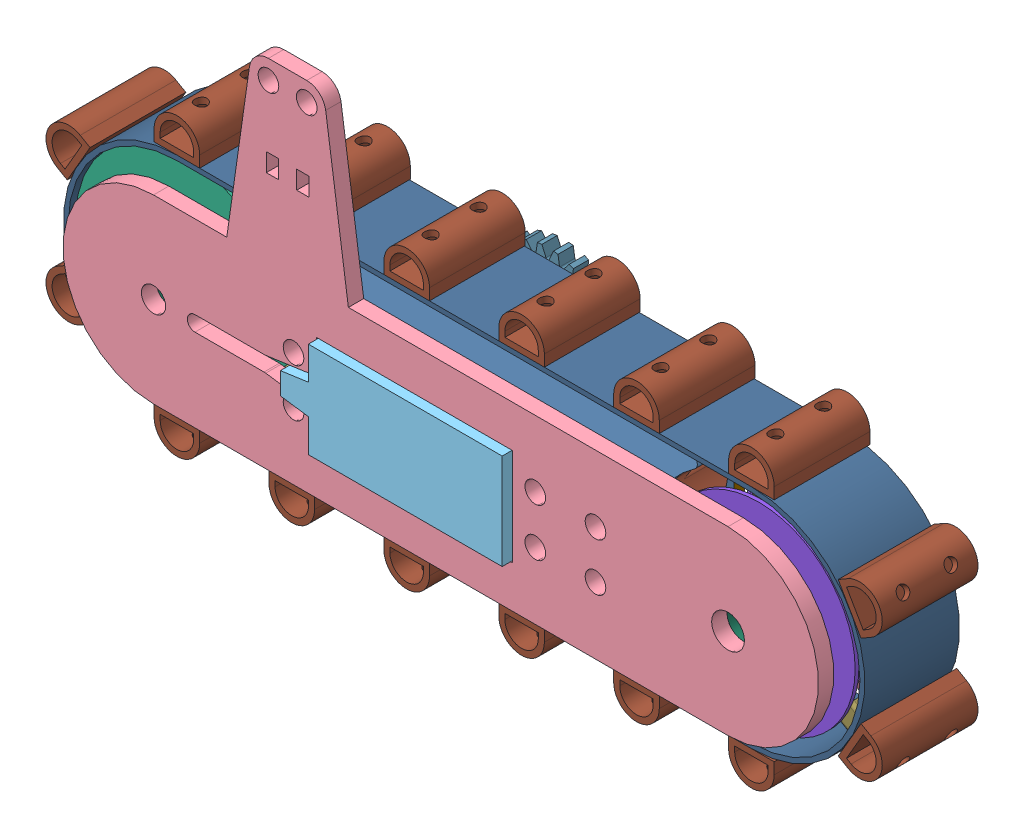
SolidWorks assembly DriveTread Assembly_L, configuration Default. Lengths in mm.
Overall size (178.72 86.46 42.8).
83 component instances, 16 part files, 32 mates.
Components (placement in the parent):
- tread runner-3: tread runner [Default] at (113.4402 41.5963 5.7004) x (-1 0 0) z (0 0 1) size (94.4 45.38 1.65)
- drive spacer_mid-1: drive spacer_mid [Default] at (14.0238 -0.101 14.8444) size (83.18 38.02 14.99)
- tread runner-4: tread runner [Default] at (113.4402 41.5963 22.3374) x (-1 0 0) z (0 0 1) size (94.4 45.38 1.65)
- drive spacer_out-1: drive spacer_out [Default] at (19.9176 6.2078 23.9884) size (78.33 25.4 3.2)
- drive plate_out-1: drive plate_out [Default] at (0 0 27.1888) size (157.83 74.53 3.2)
- Servo_ContRotation-3: Servo_ContRotation [Default] at (74.747 28.9078 5.7004) x (0 -1 0) z (0 0 -1) size (20 55.5 42.8)
- DriveWheel-4: DriveWheel [Default] at (15.6211 -3.6734 -29.9998) x (0.924613 0.380909 0) z (0 0 1) size (45.38 45.43 18.29)
  - Custom Axle Drive_LEGO UWheel_6x3-1: Custom Axle Drive_LEGO UWheel_6x3 [Default] at (-5.8421 26.8291 44.8442) size (45.38 45.43 18.29)
  - WheelPlates w-Custom Axle-1: WheelPlates w-Custom Axle [Default] at (-5.8421 26.8291 50.737) x (0.5 -0.866025 0) z (0 0 1) size (28.95 30.08 3.2)
  - WheelPlates w-Custom Axle-2: WheelPlates w-Custom Axle [Default] at (-5.8421 26.8291 35.751) x (0.5 -0.866025 0) z (0 0 1) size (28.95 30.08 3.2)
- Custom Axle Float_LEGO UWheel_6xRR2-5: Custom Axle Float_LEGO UWheel_6xRR2 [Default] at (120.015 18.9078 14.8444) x (0.969727 -0.244192 0) z (0 0 1) size (40.3 40.3 18.29)
- drive spacer_in-4: drive spacer_in [Default] at (88.0272 6.2078 3.389) x (1 0 0) z (0 0 1) size (12.43 25.4 2.31)
- tread-2: tread [Default] at (0 -3.7808 15.6064) size (178.18 61.66 20)
  - tread_base-1: tread_base [Default] at origin size (167.39 47.38 19.81)
  - D-Lug_Terrain-1: D-Lug_Terrain [Default] at (0 48.7584 -10.094) size (9.53 7.14 20)
  - D-Lug_Terrain-2: D-Lug_Terrain [Default] at (-22.5771 35.7234 -10.094) x (0.5 0.866025 0) z (0 0 1) size (9.53 7.14 20)
  - D-Lug_Terrain-3: D-Lug_Terrain [Default] at (-22.5771 9.6536 -10.094) x (-0.5 0.866025 0) z (0 0 1) size (9.53 7.14 20)
  - D-Lug_Terrain-4: D-Lug_Terrain [Default] at (0 -3.3813 -10.094) x (-1 0 0) z (0 0 1) size (9.53 7.14 20)
  - D-Lug_Terrain-6: D-Lug_Terrain [Default] at (24.003 48.7584 -10.094) size (9.53 7.14 20)
  - D-Lug_Terrain-7: D-Lug_Terrain [Default] at (48.006 48.7584 -10.094) size (9.53 7.14 20)
  - D-Lug_Terrain-8: D-Lug_Terrain [Default] at (72.009 48.7584 -10.094) size (9.53 7.14 20)
  - D-Lug_Terrain-9: D-Lug_Terrain [Default] at (96.012 48.7584 -10.094) size (9.53 7.14 20)
  - D-Lug_Terrain-10: D-Lug_Terrain [Default] at (120.015 48.7584 -10.094) size (9.53 7.14 20)
  - D-Lug_Terrain-11: D-Lug_Terrain [Default] at (24.003 -3.3813 -10.094) x (-1 0 0) z (0 0 1) size (9.53 7.14 20)
  - D-Lug_Terrain-12: D-Lug_Terrain [Default] at (48.006 -3.3813 -10.094) x (-1 0 0) z (0 0 1) size (9.53 7.14 20)
  - D-Lug_Terrain-13: D-Lug_Terrain [Default] at (72.009 -3.3813 -10.094) x (-1 0 0) z (0 0 1) size (9.53 7.14 20)
  - D-Lug_Terrain-14: D-Lug_Terrain [Default] at (96.012 -3.3813 -10.094) x (-1 0 0) z (0 0 1) size (9.53 7.14 20)
  - D-Lug_Terrain-15: D-Lug_Terrain [Default] at (142.5921 35.7234 -10.094) x (0.5 -0.866025 0) z (0 0 1) size (9.53 7.14 20)
  - D-Lug_Terrain-16: D-Lug_Terrain [Default] at (142.5921 9.6536 -10.094) x (-0.5 -0.866025 0) z (0 0 1) size (9.53 7.14 20)
  - D-Lug_Terrain-17: D-Lug_Terrain [Default] at (120.015 -3.3813 -10.094) x (-1 0 0) z (0 0 1) size (9.53 7.14 20)
  - DriveLug_x-1: DriveLug_x [Default] at (-2.7045 0 0) size (5.84 6.24 14.92)
    - Drive Lug_x-1: Drive Lug_x [Default] at origin size (5.41 3.2 14.92)
    - 97334A104_NYLON SOCKET HEAD CAP SCREW-1: 97334A104_NYLON SOCKET HEAD CAP SCREW [97334A104] at (2.7045 0.0254 0) x (0.302379 0 0.953188) z (0 -1 0) size (4.65 4.65 6.24)
  - DriveLug_x-2: DriveLug_x [Default] at (-21.0011 13.6864 0) x (0.5 -0.866025 0) z (0 0 1) size (5.84 6.24 14.92)
    - Drive Lug_x-1: Drive Lug_x [Default] at origin size (5.41 3.2 14.92)
    - 97334A104_NYLON SOCKET HEAD CAP SCREW-1: 97334A104_NYLON SOCKET HEAD CAP SCREW [97334A104] at (2.7045 0.0254 0) x (0.302379 0 0.953188) z (0 -1 0) size (4.65 4.65 6.24)
  - DriveLug_x-3: DriveLug_x [Default] at (-18.2966 36.375 0) x (-0.5 -0.866025 0) z (0 0 1) size (5.84 6.24 14.92)
    - Drive Lug_x-1: Drive Lug_x [Default] at origin size (5.41 3.2 14.92)
    - 97334A104_NYLON SOCKET HEAD CAP SCREW-1: 97334A104_NYLON SOCKET HEAD CAP SCREW [97334A104] at (2.7045 0.0254 0) x (0.302379 0 0.953188) z (0 -1 0) size (4.65 4.65 6.24)
  - DriveLug_x-4: DriveLug_x [Default] at (2.7045 45.3771 0) x (-1 0 0) z (0 0 1) size (5.84 6.24 14.92)
    - Drive Lug_x-1: Drive Lug_x [Default] at origin size (5.41 3.2 14.92)
    - 97334A104_NYLON SOCKET HEAD CAP SCREW-1: 97334A104_NYLON SOCKET HEAD CAP SCREW [97334A104] at (2.7045 0.0254 0) x (0.302379 0 0.953188) z (0 -1 0) size (4.65 4.65 6.24)
  - DriveLug_x-5: DriveLug_x [Default] at (21.2985 0 0) size (5.84 6.24 14.92)
    - Drive Lug_x-1: Drive Lug_x [Default] at origin size (5.41 3.2 14.92)
    - 97334A104_NYLON SOCKET HEAD CAP SCREW-1: 97334A104_NYLON SOCKET HEAD CAP SCREW [97334A104] at (2.7045 0.0254 0) x (0.302379 0 0.953188) z (0 -1 0) size (4.65 4.65 6.24)
  - DriveLug_x-6: DriveLug_x [Default] at (45.3015 0 0) size (5.84 6.24 14.92)
    - Drive Lug_x-1: Drive Lug_x [Default] at origin size (5.41 3.2 14.92)
    - 97334A104_NYLON SOCKET HEAD CAP SCREW-1: 97334A104_NYLON SOCKET HEAD CAP SCREW [97334A104] at (2.7045 0.0254 0) x (0.302379 0 0.953188) z (0 -1 0) size (4.65 4.65 6.24)
  - DriveLug_x-7: DriveLug_x [Default] at (69.3045 0 0) size (5.84 6.24 14.92)
    - Drive Lug_x-1: Drive Lug_x [Default] at origin size (5.41 3.2 14.92)
    - 97334A104_NYLON SOCKET HEAD CAP SCREW-1: 97334A104_NYLON SOCKET HEAD CAP SCREW [97334A104] at (2.7045 0.0254 0) x (0.302379 0 0.953188) z (0 -1 0) size (4.65 4.65 6.24)
  - DriveLug_x-8: DriveLug_x [Default] at (93.3075 0 0) size (5.84 6.24 14.92)
    - Drive Lug_x-1: Drive Lug_x [Default] at origin size (5.41 3.2 14.92)
    - 97334A104_NYLON SOCKET HEAD CAP SCREW-1: 97334A104_NYLON SOCKET HEAD CAP SCREW [97334A104] at (2.7045 0.0254 0) x (0.302379 0 0.953188) z (0 -1 0) size (4.65 4.65 6.24)
  - DriveLug_x-9: DriveLug_x [Default] at (117.3105 0 0) size (5.84 6.24 14.92)
    - Drive Lug_x-1: Drive Lug_x [Default] at origin size (5.41 3.2 14.92)
    - 97334A104_NYLON SOCKET HEAD CAP SCREW-1: 97334A104_NYLON SOCKET HEAD CAP SCREW [97334A104] at (2.7045 0.0254 0) x (0.302379 0 0.953188) z (0 -1 0) size (4.65 4.65 6.24)
  - DriveLug_x-10: DriveLug_x [Default] at (138.3116 9.0021 0) x (0.5 0.866025 0) z (0 0 1) size (5.84 6.24 14.92)
    - Drive Lug_x-1: Drive Lug_x [Default] at origin size (5.41 3.2 14.92)
    - 97334A104_NYLON SOCKET HEAD CAP SCREW-1: 97334A104_NYLON SOCKET HEAD CAP SCREW [97334A104] at (2.7045 0.0254 0) x (0.302379 0 0.953188) z (0 -1 0) size (4.65 4.65 6.24)
  - DriveLug_x-11: DriveLug_x [Default] at (141.0161 31.6907 0) x (-0.5 0.866025 0) z (0 0 1) size (5.84 6.24 14.92)
    - Drive Lug_x-1: Drive Lug_x [Default] at origin size (5.41 3.2 14.92)
    - 97334A104_NYLON SOCKET HEAD CAP SCREW-1: 97334A104_NYLON SOCKET HEAD CAP SCREW [97334A104] at (2.7045 0.0254 0) x (0.302379 0 0.953188) z (0 -1 0) size (4.65 4.65 6.24)
  - DriveLug_x-12: DriveLug_x [Default] at (122.7195 45.3771 0) x (-1 0 0) z (0 0 1) size (5.84 6.24 14.92)
    - Drive Lug_x-1: Drive Lug_x [Default] at origin size (5.41 3.2 14.92)
    - 97334A104_NYLON SOCKET HEAD CAP SCREW-1: 97334A104_NYLON SOCKET HEAD CAP SCREW [97334A104] at (2.7045 0.0254 0) x (0.302379 0 0.953188) z (0 -1 0) size (4.65 4.65 6.24)
  - DriveLug_x-13: DriveLug_x [Default] at (26.7075 45.3771 0) x (-1 0 0) z (0 0 1) size (5.84 6.24 14.92)
    - Drive Lug_x-1: Drive Lug_x [Default] at origin size (5.41 3.2 14.92)
    - 97334A104_NYLON SOCKET HEAD CAP SCREW-1: 97334A104_NYLON SOCKET HEAD CAP SCREW [97334A104] at (2.7045 0.0254 0) x (0.302379 0 0.953188) z (0 -1 0) size (4.65 4.65 6.24)
  - DriveLug_x-14: DriveLug_x [Default] at (50.7105 45.3771 0) x (-1 0 0) z (0 0 1) size (5.84 6.24 14.92)
    - Drive Lug_x-1: Drive Lug_x [Default] at origin size (5.41 3.2 14.92)
    - 97334A104_NYLON SOCKET HEAD CAP SCREW-1: 97334A104_NYLON SOCKET HEAD CAP SCREW [97334A104] at (2.7045 0.0254 0) x (0.302379 0 0.953188) z (0 -1 0) size (4.65 4.65 6.24)
  - DriveLug_x-15: DriveLug_x [Default] at (74.7135 45.3771 0) x (-1 0 0) z (0 0 1) size (5.84 6.24 14.92)
    - Drive Lug_x-1: Drive Lug_x [Default] at origin size (5.41 3.2 14.92)
    - 97334A104_NYLON SOCKET HEAD CAP SCREW-1: 97334A104_NYLON SOCKET HEAD CAP SCREW [97334A104] at (2.7045 0.0254 0) x (0.302379 0 0.953188) z (0 -1 0) size (4.65 4.65 6.24)
  - DriveLug_x-16: DriveLug_x [Default] at (98.7165 45.3771 0) x (-1 0 0) z (0 0 1) size (5.84 6.24 14.92)
    - Drive Lug_x-1: Drive Lug_x [Default] at origin size (5.41 3.2 14.92)
    - 97334A104_NYLON SOCKET HEAD CAP SCREW-1: 97334A104_NYLON SOCKET HEAD CAP SCREW [97334A104] at (2.7045 0.0254 0) x (0.302379 0 0.953188) z (0 -1 0) size (4.65 4.65 6.24)
- 24T Gear _Futaba Spline-2: 24T Gear _Futaba Spline [Default] at (44.647 18.9078 -10.5017) size (25.67 25.67 3.2)
- wheelspacer_out-1: wheelspacer_out [Default] at (120.015 18.9078 23.9884) size (19.05 19.05 3.2)
- wheelspacer_out-2: wheelspacer_out [Default] at (0 18.9078 23.9884) size (19.05 19.05 3.2)
- wheelspacer_in-1: wheelspacer_in [Default] at (120.015 18.9078 3.5668) size (19.05 19.05 2.13)
- wheelspacer_in-2: wheelspacer_in [Default] at (0 18.9078 3.5668) size (19.05 19.05 2.13)
Mates (geometry in assembly coordinates):
- Coincident6: coincident: plane of tread runner-3 through (120.015 18.9078 7.3514) normal (0 0 1); plane of drive spacer_mid-1 through (0 18.9078 7.3514) normal (0 0 -1)
- Coincident8: coincident: plane of drive spacer_mid-1 through (0 18.9078 22.3374) normal (0 0 1); plane of tread runner-4 through (120.015 18.9078 22.3374) normal (0 0 -1)
- Concentric15: concentric: cylinder of drive spacer_mid-1 through (29.247 13.9078 1.2448) axis (0 0 1) radius 2.159; cylinder of tread runner-4 through (29.247 13.9078 16.2308) axis (0 0 1) radius 2.159
- Coincident9: coincident: plane of tread runner-4 through (120.015 18.9078 23.9884) normal (0 0 1); plane of drive spacer_out-1 through (0 18.9078 23.9884) normal (0 0 -1)
- Concentric17: concentric: cylinder of tread runner-4 through (29.247 13.9078 16.2308) axis (0 0 1) radius 2.159; cylinder of drive spacer_out-1 through (29.247 13.9078 17.8818) axis (0 0 1) radius 2.159
- Concentric18: concentric: cylinder of tread runner-4 through (79.747 23.9078 16.2308) axis (0 0 1) radius 2.159; cylinder of drive spacer_out-1 through (79.747 23.9078 17.8818) axis (0 0 1) radius 2.159
- Coincident11: coincident: plane of drive spacer_out-1 through (0 18.9078 27.1888) normal (0 0 1); plane of drive plate_out-1 through (0 18.9078 27.1888) normal (0 0 -1)
- Concentric21: concentric: cylinder of drive spacer_out-1 through (29.247 23.9078 17.8818) axis (0 0 1) radius 2.159; cylinder of drive plate_out-1 through (29.247 23.9078 30.3892) axis (0 0 -1) radius 2.159
- Concentric39: concentric: cylinder of tread runner-3 through (79.747 13.9078 -0.4062) axis (0 0 1) radius 2.159; cylinder of drive spacer_mid-1 through (79.747 13.9078 1.2448) axis (0 0 1) radius 2.159
- Concentric40: concentric: cylinder of tread runner-3 through (29.247 23.9078 -0.4062) axis (0 0 1) radius 2.159; cylinder of drive spacer_mid-1 through (29.247 23.9078 1.2448) axis (0 0 1) radius 2.159
- Coincident22: coincident: plane of tread runner-3 through (120.015 18.9078 5.7004) normal (0 0 -1); plane of Servo_ContRotation-3 through (74.747 28.9078 5.7004) normal (0 0 1)
- Concentric45: concentric: cylinder of drive spacer_mid-1 through (29.247 23.9078 1.2448) axis (0 0 1) radius 2.159; cylinder of Servo_ContRotation-3 through (29.247 23.9078 3.2004) axis (0 0 1) radius 2.25
- Coincident25: coincident: plane of tread runner-4 through (120.015 18.9078 23.9884) normal (0 0 1); plane of DriveWheel-4/Custom Axle Drive_LEGO UWheel_6x3-1 through (0 18.9078 23.9884) normal (0 0 1)
- Coincident26: coincident: plane of tread runner-4 through (120.015 18.9078 23.9884) normal (0 0 1); plane of Custom Axle Float_LEGO UWheel_6xRR2-5 through (120.015 18.9078 23.9884) normal (0 0 1)
- Coincident30: coincident: plane of tread runner-3 through (120.015 18.9078 5.7004) normal (0 0 -1); plane of drive spacer_in-4 through (120.015 18.9078 5.7004) normal (0 0 1)
- Concentric55: concentric: cylinder of tread runner-3 through (120.015 18.9078 7.3514) axis (0 0 -1) radius 23.622; cylinder of drive spacer_in-4 through (120.015 18.9078 5.7004) axis (0 0 -1) radius 23.622
- Parallel4: parallel: plane of tread runner-3 through (113.4402 41.5963 7.3514) normal (0 1 0); plane of drive spacer_in-4 through (100.0974 31.6078 5.7004) normal (0 1 0)
- Concentric62: concentric: cylinder of drive spacer_mid-1 through (92.3222 23.9078 1.2448) axis (0 0 1) radius 2.159; cylinder of tread runner-4 through (92.3222 23.9078 16.2308) axis (0 0 1) radius 2.159
- Concentric63: concentric: cylinder of drive spacer_out-1 through (92.3222 13.9078 17.8818) axis (0 0 1) radius 2.159; cylinder of drive plate_out-1 through (92.3222 13.9078 30.3892) axis (0 0 -1) radius 2.159
- Concentric64: concentric: cylinder of drive plate_out-1 through (120.015 18.9078 30.3892) axis (0 0 -1) radius 3.429; cylinder of tread-2/tread_base-1 through (120.015 18.9078 25.5124) axis (0 0 -1) radius 22.6885
- Coincident34: coincident: plane of Custom Axle Float_LEGO UWheel_6xRR2-5 through (120.015 18.9078 5.7004) normal (0 0 -1); plane of tread-2/tread_base-1 through (120.015 18.9078 5.7004) normal (0 0 -1)
- Coincident36: coincident: plane of Servo_ContRotation-3 through (44.647 18.9078 -10.5017) normal (0 0 -1); plane of 24T Gear _Futaba Spline-2 through (44.647 18.9078 -10.5017) normal (0 0 -1)
- Concentric68: concentric: cylinder of Servo_ContRotation-3 through (44.647 18.9078 -10.5017) axis (0 0 1) radius 2.794; circle of 24T Gear _Futaba Spline-2
- Concentric76: concentric: cylinder of DriveWheel-4/Custom Axle Drive_LEGO UWheel_6x3-1 through (0 18.9078 23.9884) axis (0 0 -1) radius 22.6885; cylinder of tread-2/tread_base-1 through (0 18.9078 25.5124) axis (0 0 -1) radius 22.6885
- Coincident37: coincident: plane of Custom Axle Float_LEGO UWheel_6xRR2-5 through (120.015 18.9078 23.9884) normal (0 0 1); plane of wheelspacer_out-1 through (120.015 18.9078 23.9884) normal (0 0 -1)
- Concentric77: concentric: cylinder of Custom Axle Float_LEGO UWheel_6xRR2-5 through (120.015 18.9078 23.9884) axis (0 0 -1) radius 3.429; cylinder of wheelspacer_out-1 through (120.015 18.9078 27.1888) axis (0 0 -1) radius 3.429
- Coincident38: coincident: plane of DriveWheel-4/Custom Axle Drive_LEGO UWheel_6x3-1 through (0 18.9078 23.9884) normal (0 0 1); plane of wheelspacer_out-2 through (0 18.9078 23.9884) normal (0 0 -1)
- Concentric78: concentric: cylinder of drive plate_out-1 through (0 18.9078 30.3892) axis (0 0 -1) radius 2.54; cylinder of wheelspacer_out-2 through (0 18.9078 27.1888) axis (0 0 -1) radius 9.525
- Coincident39: coincident: plane of Custom Axle Float_LEGO UWheel_6xRR2-5 through (120.015 18.9078 5.7004) normal (0 0 -1); plane of wheelspacer_in-1 through (120.015 18.9078 5.7004) normal (0 0 1)
- Concentric79: concentric: cylinder of Custom Axle Float_LEGO UWheel_6xRR2-5 through (120.015 18.9078 23.9884) axis (0 0 -1) radius 3.429; cylinder of wheelspacer_in-1 through (120.015 18.9078 5.7004) axis (0 0 -1) radius 3.429
- Coincident40: coincident: plane of DriveWheel-4/Custom Axle Drive_LEGO UWheel_6x3-1 through (0 18.9078 5.7004) normal (0 0 -1); plane of wheelspacer_in-2 through (0 18.9078 5.7004) normal (0 0 1)
- Concentric80: concentric: cylinder of drive plate_out-1 through (0 18.9078 30.3892) axis (0 0 -1) radius 2.54; circle of wheelspacer_in-2
